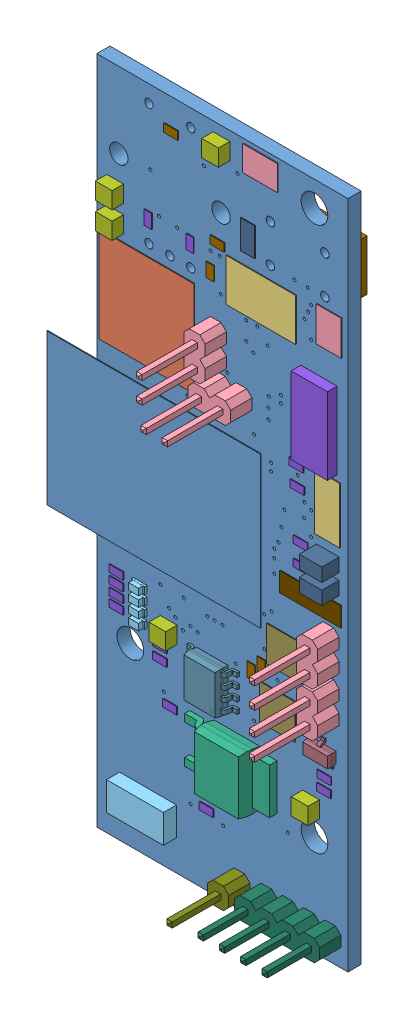
SolidWorks assembly main_board v16, configuration Default. Lengths in mm.
Overall size (35.87 80 13.3).
82 component instances, 28 part files, 0 mates.
Components (placement in the parent):
- main_board v16.step-1: main_board v16.step [Default] at origin size (35.87 80 13.3)
  - PCB Component.step-1: PCB Component.step [Default] at origin size (35.87 80 13.3)
    - Board.step-1: Board.step [Default] at origin size (30 80 1.57)
    - 10u.step-1: 10u.step [Default] at (13.12 6.66 0) x (1 0 0) z (0 0 -1) size (2.2 1.45 0.1)
    - 10u.step-2: 10u.step [Default] at (12.2 51.6 1.57) x (0 1 0) z (0 0 1) size (2.2 1.45 0.1)
    - SOP65P640X120-17N.step-1: SOP65P640X120-17N.step [Default] at (20.55 64.42 1.57) x (-1 0 0) z (0 0 1) size (8.31 5.08 0.1)
    - PINH2X02SMD.step-1: PINH2X02SMD.step [Default] at (25.79 65.24 1.57) x (0 1 0) z (0 0 1) size (4.14 3 0.1)
    - PINH2X02SMD.step-2: PINH2X02SMD.step [Default] at (19.6 76 1.57) x (-1 0 0) z (0 0 1) size (4.14 3 0.1)
    - blue.step-1: blue.step [Default] at (5.18 23.96 1.57) x (0 1 0) z (0 0 1) size (0.8 1.6 0.8)
    - blue.step-2: blue.step [Default] at (5.2 25.2 1.57) x (0 1 0) z (0 0 1) size (0.8 1.6 0.8)
    - blue.step-3: blue.step [Default] at (5.2 26.4 1.57) x (0 1 0) z (0 0 1) size (0.8 1.6 0.8)
    - blue.step-4: blue.step [Default] at (5.2 27.6 1.57) x (0 1 0) z (0 0 1) size (0.8 1.6 0.8)
    - IRFR5305.step-1: IRFR5305.step [Default] at (4.15 13.31 0) x (1 0 0) z (0 0 -1) size (6.73 10.41 2.39)
    - IRFR5305.step-2: IRFR5305.step [Default] at (16.29 14.88 1.57) x (0 -1 0) z (0 0 1) size (6.73 10.41 2.39)
    - 2N7002.step-1: 2N7002.step [Default] at (12.33 10 0) x (0 -1 0) z (0 0 -1) size (2.84 2.59 0.1)
    - 330.step-1: 330.step [Default] at (8.81 16.89 1.57) size (1.68 0.86 0.1)
    - 330.step-2: 330.step [Default] at (13.16 8.44 1.57) size (1.68 0.86 0.1)
    - 330.step-3: 330.step [Default] at (15.2 50.6 1.57) size (1.68 0.86 0.1)
    - 330.step-4: 330.step [Default] at (8.78 50.6 0) x (1 0 0) z (0 0 -1) size (1.68 0.86 0.1)
    - 330.step-5: 330.step [Default] at (7.6 22.6 1.57) x (-1 0 0) z (0 0 1) size (1.68 0.86 0.1)
    - 330.step-6: 330.step [Default] at (7.6 21.2 1.57) size (1.68 0.86 0.1)
    - 330.step-7: 330.step [Default] at (2.4 24 1.57) size (1.68 0.86 0.1)
    - 330.step-8: 330.step [Default] at (2.4 25.2 1.57) size (1.68 0.86 0.1)
    - 330.step-9: 330.step [Default] at (2.4 26.4 1.57) size (1.68 0.86 0.1)
    - 330.step-10: 330.step [Default] at (27.21 18.78 1.57) x (-1 0 0) z (0 0 1) size (1.68 0.86 0.1)
    - 330.step-11: 330.step [Default] at (27.19 17.41 1.57) size (1.68 0.86 0.1)
    - 330.step-12: 330.step [Default] at (18 42.4 0) x (1 0 0) z (0 0 -1) size (1.68 0.86 0.1)
    - 330.step-13: 330.step [Default] at (15.9 42.8 0) x (0 -1 0) z (0 0 -1) size (1.68 0.86 0.1)
    - 330.step-14: 330.step [Default] at (24.4 41.6 1.57) size (1.68 0.86 0.1)
    - 330.step-15: 330.step [Default] at (24.4 39.19 1.57) size (1.68 0.86 0.1)
    - 330.step-16: 330.step [Default] at (23.9 49.44 1.57) size (1.68 0.86 0.1)
    - 330.step-17: 330.step [Default] at (24 47.2 1.57) size (1.68 0.86 0.1)
    - 330.step-18: 330.step [Default] at (9 31.56 0) x (1 0 0) z (0 0 -1) size (1.68 0.86 0.1)
    - 330.step-19: 330.step [Default] at (9.32 44.66 0) x (1 0 0) z (0 0 -1) size (1.68 0.86 0.1)
    - 330.step-20: 330.step [Default] at (11.2 66 1.57) x (0 1 0) z (0 0 1) size (1.68 0.86 0.1)
    - 330.step-21: 330.step [Default] at (6.2 66 1.57) x (0 1 0) z (0 0 1) size (1.68 0.86 0.1)
    - 330.step-22: 330.step [Default] at (12.3 54.8 0) x (0 -1 0) z (0 0 -1) size (1.68 0.86 0.1)
    - 330.step-23: 330.step [Default] at (15.57 45.84 0) x (-1 0 0) z (0 0 -1) size (1.68 0.86 0.1)
    - 330.step-24: 330.step [Default] at (2.4 27.6 1.57) size (1.68 0.86 0.1)
    - 100n.step-1: 100n.step [Default] at (13.6 64.3 1.57) x (0 1 0) z (0 0 1) size (1.67 0.95 0.1)
    - 100n.step-2: 100n.step [Default] at (14.47 67.64 1.57) x (-1 0 0) z (0 0 1) size (1.67 0.95 0.1)
    - 100n.step-3: 100n.step [Default] at (19.7 26.5 1.57) x (0 -1 0) z (0 0 1) size (1.67 0.95 0.1)
    - 100n.step-4: 100n.step [Default] at (15.87 20.36 0) x (0 1 0) z (0 0 -1) size (1.67 0.95 0.1)
    - 100n.step-5: 100n.step [Default] at (27.2 39.2 0) x (-1 0 0) z (0 0 -1) size (1.67 0.95 0.1)
    - 100n.step-6: 100n.step [Default] at (27.2 41.6 0) x (-1 0 0) z (0 0 -1) size (1.67 0.95 0.1)
    - 100n.step-7: 100n.step [Default] at (18.5 25.4 1.57) x (0 1 0) z (0 0 1) size (1.67 0.95 0.1)
    - 100n.step-8: 100n.step [Default] at (8 32.93 0) x (1 0 0) z (0 0 -1) size (1.67 0.95 0.1)
    - 100n.step-9: 100n.step [Default] at (6.86 36.7 0) x (0 1 0) z (0 0 -1) size (1.67 0.95 0.1)
    - 100n.step-10: 100n.step [Default] at (8.25 36.7 0) x (0 1 0) z (0 0 -1) size (1.67 0.95 0.1)
    - 100n.step-11: 100n.step [Default] at (8.92 76.42 1.57) size (1.67 0.95 0.1)
    - 100n.step-12: 100n.step [Default] at (15.57 47.23 0) x (-1 0 0) z (0 0 -1) size (1.67 0.95 0.1)
    - 10u_1.step-1: 10u_1.step [Default] at (18.09 70 1.57) x (0 1 0) z (0 0 1) size (3.4 1.7 0.1)
    - LFDPAK_C.step-1: LFDPAK_C.step [Default] at (20.64 29.25 0) x (0 1 0) z (0 0 -1) size (6.35 9.25 0.1)
    - LFDPAK_C.step-2: LFDPAK_C.step [Default] at (23.44 20.83 0) x (0 1 0) z (0 0 -1) size (6.35 9.25 0.1)
    - 2u2.step-1: 2u2.step [Default] at (22.46 29.21 1.57) x (0 1 0) z (0 0 1) size (4.2 4.2 0.1)
    - 2u2.step-2: 2u2.step [Default] at (21.66 22.79 1.57) x (0 1 0) z (0 0 1) size (4.2 4.2 0.1)
    - BC817.step-1: BC817.step [Default] at (27.19 21.57 1.57) size (3.04 2.64 1.12)
    - BC817.step-2: BC817.step [Default] at (21.46 49.7 0) x (0 -1 0) z (0 0 -1) size (3.04 2.64 1.12)
    - BC817.step-3: BC817.step [Default] at (21.41 46.1 0) x (0 -1 0) z (0 0 -1) size (3.04 2.64 1.12)
    - MCP3202SN.step-1: MCP3202SN.step [Default] at (14.02 22.43 1.57) x (0 -1 0) z (0 0 1) size (4.9 6 1.75)
    - STEPDOWN.step-1: STEPDOWN.step [Default] at (24.04 2.73 1.57) size (10.16 2.54 11.34)
    - 1X01.step-1: 1X01.step [Default] at (17.03 2.71 1.57) size (2.54 2.54 11.54)
    - Si4134.step-1: Si4134.step [Default] at (17.08 37.39 0) x (0 -1 0) z (0 0 -1) size (5.74 4.72 0.1)
    - SK34.step-1: SK34.step [Default] at (25.6 36.4 1.57) x (-1 0 0) z (0 0 1) size (7.31 2.3 0.1)
    - ESP-WROOM-32.step-1: ESP-WROOM-32.step [Default] at (8.63 39.44 1.57) x (0 1 0) z (0 0 1) size (18 25.5 0.1)
    - PIEZO.step-1: PIEZO.step [Default] at (11.1 55.13 1.57) x (0 1 0) z (0 0 1) size (11.36 11.36 0.1)
    - PINH2X03SMD.step-1: PINH2X03SMD.step [Default] at (25.6 46.8 1.57) x (0 1 0) z (0 0 1) size (6.68 3 0.1)
    - VIBRATE_SW.step-1: VIBRATE_SW.step [Default] at (16 53 1.57) size (5.08 2.54 12.64)
    - VIBRATE_SW.step-2: VIBRATE_SW.step [Default] at (27.68 26.86 1.57) x (0 1 0) z (0 0 1) size (5.08 2.54 12.64)
    - VIBRATE_SW.step-3: VIBRATE_SW.step [Default] at (27.68 32.21 1.57) x (0 1 0) z (0 0 1) size (5.08 2.54 12.64)
    - VIBRATE_SW.step-4: VIBRATE_SW.step [Default] at (14.23 57.06 1.57) x (0 1 0) z (0 0 1) size (5.08 2.54 12.64)
    - POWER_IN.step-1: POWER_IN.step [Default] at (6.12 5.98 1.57) size (6.78 3.4 1.56)
    - EC12E_SW.step-1: EC12E_SW.step [Default] at (8.73 70.96 0) x (-1 0 0) z (0 0 -1) size (14.91 16.01 0.73)
    - TPSQTP20SQ.step-1: TPSQTP20SQ.step [Default] at (25.59 15.12 1.57) size (2 2 1.36)
    - TPSQTP20SQ.step-2: TPSQTP20SQ.step [Default] at (2.19 63.94 1.57) size (2 2 1.36)
    - TPSQTP20SQ.step-3: TPSQTP20SQ.step [Default] at (14.89 77.86 1.57) size (2 2 1.36)
    - TPSQTP20SQ.step-4: TPSQTP20SQ.step [Default] at (8.59 24.68 1.57) size (2 2 1.36)
    - TPSQTP20SQ.step-5: TPSQTP20SQ.step [Default] at (2.19 67.1 1.57) size (2 2 1.36)
    - B3F-31XX.step-1: B3F-31XX.step [Default] at (26.7 55.37 1.57) x (0 1 0) z (0 0 1) size (9.17 4.33 1.16)
    - START_BTN.step-1: START_BTN.step [Default] at (23.99 70.74 0) x (-1 0 0) z (0 0 -1) size (9.55 6.05 1.96)
    - SJ.step-1: SJ.step [Default] at (27.6 41.6 1.57) x (-1 0 0) z (0 0 1) size (2.69 1.6 2.07)
    - SJ.step-2: SJ.step [Default] at (27.6 39.2 1.57) x (-1 0 0) z (0 0 1) size (2.69 1.6 2.07)
